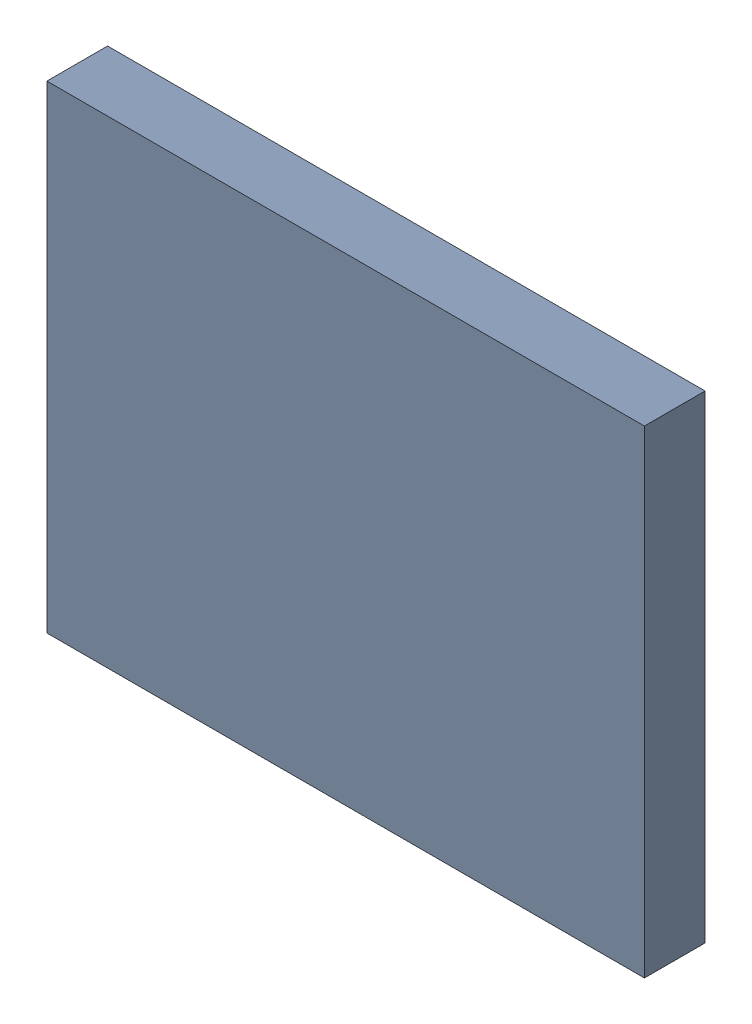
SolidWorks assembly L1, configuration 默认. Lengths in mm.
Overall size (2.5 2 0.25).
2 component instances, 1 part files, 0 mates.
Components (placement in the parent):
- 6227607856-1: 6227607856 [默认] at (114.4524 86.233 0) size (2.5 2 0.25)
  - Extruded_2-1: Extruded_2 [默认] at origin size (2.5 2 0.25)
